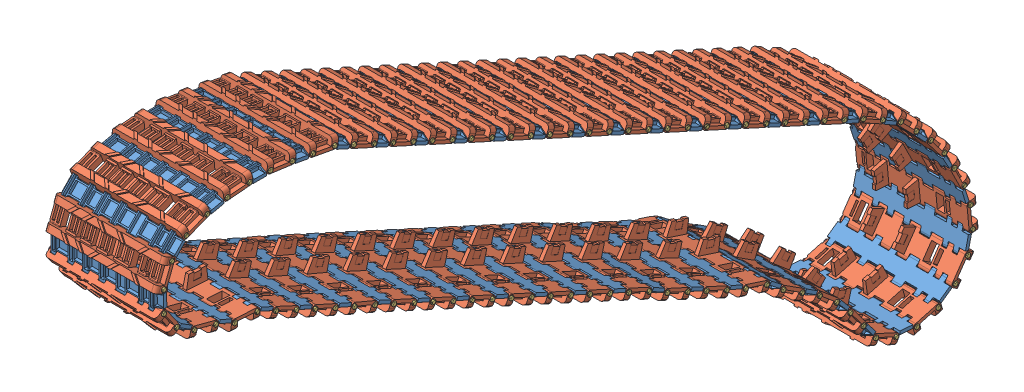
SolidWorks assembly MirrorTREAD (FINAL), configuration Default. Lengths in mm.
Overall size (22.86 95.91 166.24).
270 component instances, 4 part files, 0 mates.
Components (placement in the parent):
- Tread Part 2-1: Tread Part 2 [Default] at (0 0 -26.5717) x (-1 0 0) z (0 0 -1) size (22.53 1.27 5.46)
- Tread Part 1-1: Tread Part 1 [Default] at (20.9139 0.0325 -11.5906) x (-1 0 0) z (0 0.086807 -0.996225) size (22.53 4.95 5.79)
- Linkage Bolt-1: Linkage Bolt [Default] at (25.6791 0.635 -11.1903) x (0 -0.28534 -0.958426) z (1 0 0) size (0.89 0.89 22.86)
- Linkage Nut-1: Linkage Nut [Default] at (3.3271 0.635 -11.1903) x (0 0.279758 0.960071) z (-1 0 0) size (1.17 1.02 0.25)
- Tread Part 1-2: Tread Part 1 [Default] at (20.9139 -16.6165 -59.8831) x (-1 0 0) z (0 -0.414552 -0.910026) size (22.53 4.95 5.79)
- Tread Part 1-3: Tread Part 1 [Default] at (20.9139 -12.9594 5.7016) x (-1 0 0) z (0 0.819649 0.572866) size (22.53 4.95 5.79)
- Tread Part 1-4: Tread Part 1 [Default] at (20.9139 -9.4391 -44.1273) x (-1 0 0) z (0 -0.414552 -0.910026) size (22.53 4.95 5.79)
- Tread Part 1-5: Tread Part 1 [Default] at (20.9139 -1.1036 -3.1964) x (-1 0 0) z (0 0.360184 -0.932881) size (22.53 4.95 5.79)
- Tread Part 1-6: Tread Part 1 [Default] at (20.9139 -13.0278 -52.0052) x (-1 0 0) z (0 -0.414552 -0.910026) size (22.53 4.95 5.79)
- Tread Part 1-7: Tread Part 1 [Default] at (20.9139 -0.6492 -20.0624) x (-1 0 0) z (0 -0.136124 -0.990692) size (22.53 4.95 5.79)
- Tread Part 1-8: Tread Part 1 [Default] at (20.9139 -5.8504 -36.2493) x (-1 0 0) z (0 -0.414552 -0.910026) size (22.53 4.95 5.79)
- Tread Part 1-9: Tread Part 1 [Default] at (20.9139 -5.1562 3.7247) x (-1 0 0) z (0 0.932796 -0.360404) size (22.53 4.95 5.79)
- Tread Part 1-10: Tread Part 1 [Default] at (20.9139 -2.2276 -28.5444) x (-1 0 0) z (0 -0.182095 -0.983281) size (22.53 4.95 5.79)
- Tread Part 2-2: Tread Part 2 [Default] at (0 -15.6718 -57.8094) x (-1 0 0) z (0 -0.414552 -0.910026) size (22.53 1.27 5.46)
- Tread Part 2-3: Tread Part 2 [Default] at (0 1.9852 -17.8142) x (-1 0 0) z (0 0.210774 -0.977535) size (22.53 1.27 5.46)
- Tread Part 2-4: Tread Part 2 [Default] at (0 -3.365 -34.8217) x (-1 0 0) z (0 -0.179921 -0.983681) size (22.53 1.27 5.46)
- Tread Part 2-5: Tread Part 2 [Default] at (0 -19.2605 -65.6873) x (-1 0 0) z (0 -0.414552 -0.910026) size (22.53 1.27 5.46)
- Tread Part 2-6: Tread Part 2 [Default] at (0 1.7781 5.4907) x (-1 0 0) z (0 0.999978 0.006638) size (22.53 1.27 5.46)
- Tread Part 2-7: Tread Part 2 [Default] at (0 5.3393 -6.7315) x (-1 0 0) z (0 0.717252 -0.696814) size (22.53 1.27 5.46)
- Tread Part 2-8: Tread Part 2 [Default] at (0 -8.4944 -42.0535) x (-1 0 0) z (0 -0.414552 -0.910026) size (22.53 1.27 5.46)
- Tread Part 2-9: Tread Part 2 [Default] at (0 -22.8492 -73.5653) x (-1 0 0) z (0 -0.414552 -0.910026) size (22.53 1.27 5.46)
- Tread Part 2-10: Tread Part 2 [Default] at (0 -12.0831 -49.9315) x (-1 0 0) z (0 -0.414552 -0.910026) size (22.53 1.27 5.46)
- Linkage Bolt-2: Linkage Bolt [Default] at (25.6791 -14.0437 -55.7671) x (0 -0.279758 -0.960071) z (1 0 0) size (0.89 0.89 22.86)
- Linkage Bolt-3: Linkage Bolt [Default] at (25.6791 -8.7176 -44.0752) x (0 -0.279758 -0.960071) z (1 0 0) size (0.89 0.89 22.86)
- Linkage Bolt-4: Linkage Bolt [Default] at (25.6791 -5.1289 -36.1973) x (0 -0.279758 -0.960071) z (1 0 0) size (0.89 0.89 22.86)
- Linkage Bolt-5: Linkage Bolt [Default] at (25.6791 -12.3063 -51.9532) x (0 -0.279758 -0.960071) z (1 0 0) size (0.89 0.89 22.86)
- Linkage Bolt-6: Linkage Bolt [Default] at (25.6791 -0.727 -23.9282) x (0 0.859107 0.511795) z (1 0 0) size (0.89 0.89 22.86)
- Linkage Bolt-7: Linkage Bolt [Default] at (25.6791 -6.8663 -40.0112) x (0 -0.279758 -0.960071) z (1 0 0) size (0.89 0.89 22.86)
- Linkage Bolt-8: Linkage Bolt [Default] at (25.6791 -15.895 -59.8311) x (0 -0.279758 -0.960071) z (1 0 0) size (0.89 0.89 22.86)
- Linkage Bolt-9: Linkage Bolt [Default] at (25.6791 -3.2775 -32.1333) x (0 -0.279758 -0.960071) z (1 0 0) size (0.89 0.89 22.86)
- Linkage Bolt-10: Linkage Bolt [Default] at (25.6791 -1.5402 -28.3194) x (0 -0.279758 -0.960071) z (1 0 0) size (0.89 0.89 22.86)
- Linkage Bolt-11: Linkage Bolt [Default] at (25.6791 -10.455 -47.8891) x (0 -0.279758 -0.960071) z (1 0 0) size (0.89 0.89 22.86)
- Linkage Bolt-12: Linkage Bolt [Default] at (25.6791 -17.2675 3.4653) x (0 -0.279758 -0.960071) z (1 0 0) size (0.89 0.89 22.86)
- Linkage Bolt-13: Linkage Bolt [Default] at (25.6791 -13.6071 6.0236) x (0 -0.279758 -0.960071) z (1 0 0) size (0.89 0.89 22.86)
- Linkage Bolt-14: Linkage Bolt [Default] at (25.6791 -5.2505 4.4419) x (0 -0.50378 -0.863832) z (1 0 0) size (0.89 0.89 22.86)
- Linkage Bolt-15: Linkage Bolt [Default] at (25.6791 0.0271 -19.8056) x (0 0.965901 0.258913) z (1 0 0) size (0.89 0.89 22.86)
- Linkage Bolt-16: Linkage Bolt [Default] at (25.6791 0.2473 -6.7414) x (0 -0.279758 -0.960071) z (1 0 0) size (0.89 0.89 22.86)
- Linkage Bolt-17: Linkage Bolt [Default] at (25.6791 -2.2445 1.5215) x (0 -0.279758 -0.960071) z (1 0 0) size (0.89 0.89 22.86)
- Linkage Bolt-18: Linkage Bolt [Default] at (25.6791 -9.4162 6.0514) x (0 -0.820255 0.571998) z (1 0 0) size (0.89 0.89 22.86)
- Linkage Bolt-19: Linkage Bolt [Default] at (25.6791 0.635 -15.3813) x (0 -0.279758 -0.960071) z (1 0 0) size (0.89 0.89 22.86)
- Linkage Bolt-20: Linkage Bolt [Default] at (25.6791 -0.636 -2.6445) x (0 -0.244946 -0.969537) z (1 0 0) size (0.89 0.89 22.86)
- Linkage Nut-2: Linkage Nut [Default] at (3.0731 -0.636 -2.6445) x (0 -0.279758 -0.960071) z (1 0 0) size (1.17 1.02 0.25)
- Linkage Nut-3: Linkage Nut [Default] at (3.0731 -15.895 -59.8311) x (0 -0.279758 -0.960071) z (1 0 0) size (1.17 1.02 0.25)
- Linkage Nut-4: Linkage Nut [Default] at (3.0731 0.635 -15.3813) x (0 -0.279758 -0.960071) z (1 0 0) size (1.17 1.02 0.25)
- Linkage Nut-5: Linkage Nut [Default] at (3.0731 -14.0437 -55.7671) x (0 -0.279758 -0.960071) z (1 0 0) size (1.17 1.02 0.25)
- Linkage Nut-6: Linkage Nut [Default] at (3.0731 -3.2775 -32.1333) x (0 -0.279758 -0.960071) z (1 0 0) size (1.17 1.02 0.25)
- Linkage Nut-7: Linkage Nut [Default] at (3.0731 -5.1289 -36.1973) x (0 -0.279758 -0.960071) z (1 0 0) size (1.17 1.02 0.25)
- Linkage Nut-8: Linkage Nut [Default] at (3.0731 -1.5402 -28.3194) x (0 -0.279758 -0.960071) z (1 0 0) size (1.17 1.02 0.25)
- Linkage Nut-9: Linkage Nut [Default] at (3.0731 -6.8663 -40.0112) x (0 -0.279758 -0.960071) z (1 0 0) size (1.17 1.02 0.25)
- Linkage Nut-10: Linkage Nut [Default] at (3.0731 -0.727 -23.9282) x (0 -0.279758 -0.960071) z (1 0 0) size (1.17 1.02 0.25)
- Linkage Nut-11: Linkage Nut [Default] at (3.0731 -13.6071 6.0236) x (0 -0.279758 -0.960071) z (1 0 0) size (1.17 1.02 0.25)
- Linkage Nut-12: Linkage Nut [Default] at (3.0731 -9.4162 6.0514) x (0 -0.279758 -0.960071) z (1 0 0) size (1.17 1.02 0.25)
- Linkage Nut-13: Linkage Nut [Default] at (3.0731 -8.7176 -44.0752) x (0 -0.279758 -0.960071) z (1 0 0) size (1.17 1.02 0.25)
- Linkage Nut-14: Linkage Nut [Default] at (3.0731 0.0271 -19.8056) x (0 0.537357 -0.843355) z (1 0 0) size (1.17 1.02 0.25)
- Linkage Nut-15: Linkage Nut [Default] at (3.0731 0.2473 -6.7414) x (0 -0.279758 -0.960071) z (1 0 0) size (1.17 1.02 0.25)
- Linkage Nut-16: Linkage Nut [Default] at (3.0731 -17.2675 3.4653) x (0 -0.279758 -0.960071) z (1 0 0) size (1.17 1.02 0.25)
- Linkage Nut-17: Linkage Nut [Default] at (3.0731 -2.2445 1.5215) x (0 -0.279758 -0.960071) z (1 0 0) size (1.17 1.02 0.25)
- Linkage Nut-18: Linkage Nut [Default] at (3.0731 -5.2505 4.4419) x (0 -0.130274 -0.991478) z (1 0 0) size (1.17 1.02 0.25)
- Linkage Nut-19: Linkage Nut [Default] at (3.0731 -12.3063 -51.9532) x (0 -0.279758 -0.960071) z (1 0 0) size (1.17 1.02 0.25)
- Linkage Nut-20: Linkage Nut [Default] at (3.0731 -10.455 -47.8891) x (0 -0.279758 -0.960071) z (1 0 0) size (1.17 1.02 0.25)
- Tread Part 2-11: Tread Part 2 [Default] at (0 -44.4097 -120.8185) x (-1 0 0) z (0 -0.416427 -0.909169) size (22.53 1.27 5.46)
- Tread Part 1-11: Tread Part 1 [Default] at (20.9139 -38.1487 -107.1507) x (-1 0 0) z (0 -0.414552 -0.910026) size (22.53 4.95 5.79)
- Linkage Bolt-21: Linkage Bolt [Default] at (25.6791 -37.4272 -107.0987) x (0 -0.416427 -0.909169) z (1 0 0) size (0.89 0.89 22.86)
- Linkage Nut-21: Linkage Nut [Default] at (3.3271 -37.4272 -107.0987) x (0 0.416427 0.909169) z (-1 0 0) size (1.17 1.02 0.25)
- Tread Part 1-12: Tread Part 1 [Default] at (20.9139 -64.6898 -150.487) x (-1 0 0) z (0 -0.793222 -0.608932) size (22.53 4.95 5.79)
- Tread Part 1-13: Tread Part 1 [Default] at (20.9139 -27.3826 -83.5169) x (-1 0 0) z (0 -0.414552 -0.910026) size (22.53 4.95 5.79)
- Tread Part 1-14: Tread Part 1 [Default] at (20.9139 -52.8597 -138.4334) x (-1 0 0) z (0 -0.48122 -0.8766) size (22.53 4.95 5.79)
- Tread Part 1-15: Tread Part 1 [Default] at (20.9139 -20.2052 -67.7611) x (-1 0 0) z (0 -0.414552 -0.910026) size (22.53 4.95 5.79)
- Tread Part 1-16: Tread Part 1 [Default] at (20.9139 -23.7939 -75.639) x (-1 0 0) z (0 -0.414552 -0.910026) size (22.53 4.95 5.79)
- Tread Part 1-17: Tread Part 1 [Default] at (20.9139 -34.56 -99.2728) x (-1 0 0) z (0 -0.414552 -0.910026) size (22.53 4.95 5.79)
- Tread Part 1-18: Tread Part 1 [Default] at (20.9139 -58.1406 -144.9601) x (-1 0 0) z (0 -0.71534 -0.698777) size (22.53 4.95 5.79)
- Tread Part 1-19: Tread Part 1 [Default] at (20.9139 -41.7537 -115.0197) x (-1 0 0) z (0 -0.416427 -0.909169) size (22.53 4.95 5.79)
- Tread Part 1-20: Tread Part 1 [Default] at (20.9139 -48.9636 -130.7608) x (-1 0 0) z (0 -0.416429 -0.909168) size (22.53 4.95 5.79)
- Tread Part 1-21: Tread Part 1 [Default] at (20.9139 -30.9713 -91.3948) x (-1 0 0) z (0 -0.414552 -0.910026) size (22.53 4.95 5.79)
- Tread Part 1-22: Tread Part 1 [Default] at (20.9139 -45.3587 -122.8902) x (-1 0 0) z (0 -0.416427 -0.909169) size (22.53 4.95 5.79)
- Tread Part 2-12: Tread Part 2 [Default] at (0 -60.4579 -151.3867) x (-1 0 0) z (0 -0.505398 -0.862886) size (22.53 1.27 5.46)
- Tread Part 2-13: Tread Part 2 [Default] at (0 -40.7927 -112.9549) x (-1 0 0) z (0 -0.414552 -0.910026) size (22.53 1.27 5.46)
- Tread Part 2-14: Tread Part 2 [Default] at (0 -48.0147 -128.689) x (-1 0 0) z (0 -0.416427 -0.909169) size (22.53 1.27 5.46)
- Tread Part 2-15: Tread Part 2 [Default] at (0 -69.0325 -155.3119) x (-1 0 0) z (0 -0.724635 -0.689133) size (22.53 1.27 5.46)
- Tread Part 2-16: Tread Part 2 [Default] at (0 -33.6153 -97.199) x (-1 0 0) z (0 -0.414552 -0.910026) size (22.53 1.27 5.46)
- Tread Part 2-17: Tread Part 2 [Default] at (0 -30.0266 -89.3211) x (-1 0 0) z (0 -0.414552 -0.910026) size (22.53 1.27 5.46)
- Tread Part 2-18: Tread Part 2 [Default] at (0 -37.204 -105.077) x (-1 0 0) z (0 -0.414552 -0.910026) size (22.53 1.27 5.46)
- Tread Part 2-19: Tread Part 2 [Default] at (0 -51.6196 -136.5595) x (-1 0 0) z (0 -0.416427 -0.909169) size (22.53 1.27 5.46)
- Tread Part 2-20: Tread Part 2 [Default] at (0 -26.4379 -81.4432) x (-1 0 0) z (0 -0.414552 -0.910026) size (22.53 1.27 5.46)
- Tread Part 2-21: Tread Part 2 [Default] at (0 -77.8314 -157.5963) x (-1 0 0) z (0 -0.877598 -0.479397) size (22.53 1.27 5.46)
- Tread Part 2-22: Tread Part 2 [Default] at (0 -55.2245 -144.43) x (-1 0 0) z (0 -0.416427 -0.909169) size (22.53 1.27 5.46)
- Linkage Bolt-22: Linkage Bolt [Default] at (25.6791 -60.486 -148.0604) x (0 -0.416427 -0.909169) z (1 0 0) size (0.89 0.89 22.86)
- Linkage Bolt-23: Linkage Bolt [Default] at (25.6791 -52.1363 -138.4353) x (0 -0.99376 -0.111543) z (1 0 0) size (0.89 0.89 22.86)
- Linkage Bolt-24: Linkage Bolt [Default] at (25.6791 -48.242 -130.7102) x (0 -0.416427 -0.909169) z (1 0 0) size (0.89 0.89 22.86)
- Linkage Bolt-25: Linkage Bolt [Default] at (25.6791 -57.449 -145.1722) x (0 -0.416427 -0.909169) z (1 0 0) size (0.89 0.89 22.86)
- Linkage Bolt-26: Linkage Bolt [Default] at (25.6791 -42.7774 -118.7795) x (0 -0.416427 -0.909169) z (1 0 0) size (0.89 0.89 22.86)
- Linkage Bolt-27: Linkage Bolt [Default] at (25.6791 -49.9873 -134.5205) x (0 0.416133 -0.909304) z (1 0 0) size (0.89 0.89 22.86)
- Linkage Bolt-28: Linkage Bolt [Default] at (25.6791 -64.0283 -150.7798) x (0 -0.416427 -0.909169) z (1 0 0) size (0.89 0.89 22.86)
- Linkage Bolt-29: Linkage Bolt [Default] at (25.6791 -46.3823 -126.65) x (0 -0.416427 -0.909169) z (1 0 0) size (0.89 0.89 22.86)
- Linkage Bolt-30: Linkage Bolt [Default] at (25.6791 -44.6371 -122.8397) x (0 -0.416427 -0.909169) z (1 0 0) size (0.89 0.89 22.86)
- Linkage Bolt-31: Linkage Bolt [Default] at (25.6791 -54.2544 -142.0516) x (0 0.865619 0.500703) z (1 0 0) size (0.89 0.89 22.86)
- Linkage Bolt-32: Linkage Bolt [Default] at (25.6791 -23.0724 -75.5869) x (0 -0.416427 -0.909169) z (1 0 0) size (0.89 0.89 22.86)
- Linkage Bolt-33: Linkage Bolt [Default] at (25.6791 -24.8098 -79.4009) x (0 -0.416427 -0.909169) z (1 0 0) size (0.89 0.89 22.86)
- Linkage Bolt-34: Linkage Bolt [Default] at (25.6791 -26.6611 -83.4649) x (0 -0.416427 -0.909169) z (1 0 0) size (0.89 0.89 22.86)
- Linkage Bolt-35: Linkage Bolt [Default] at (25.6791 -30.2498 -91.3428) x (0 -0.416494 -0.909139) z (1 0 0) size (0.89 0.89 22.86)
- Linkage Bolt-36: Linkage Bolt [Default] at (25.6791 -41.0321 -114.9692) x (0 -0.416427 -0.909169) z (1 0 0) size (0.89 0.89 22.86)
- Linkage Bolt-37: Linkage Bolt [Default] at (25.6791 -35.5759 -103.0346) x (0 -0.416427 -0.909169) z (1 0 0) size (0.89 0.89 22.86)
- Linkage Bolt-38: Linkage Bolt [Default] at (25.6791 -31.9872 -95.1567) x (0 -0.416427 -0.909169) z (1 0 0) size (0.89 0.89 22.86)
- Linkage Bolt-39: Linkage Bolt [Default] at (25.6791 -28.3985 -87.2788) x (0 -0.416427 -0.909169) z (1 0 0) size (0.89 0.89 22.86)
- Linkage Bolt-40: Linkage Bolt [Default] at (25.6791 -39.1724 -110.909) x (0 0.381485 0.924375) z (1 0 0) size (0.89 0.89 22.86)
- Linkage Bolt-41: Linkage Bolt [Default] at (25.6791 -33.8385 -99.2207) x (0 -0.416427 -0.909169) z (1 0 0) size (0.89 0.89 22.86)
- Linkage Bolt-42: Linkage Bolt [Default] at (25.6791 -17.6324 -63.645) x (0 -0.416427 -0.909169) z (1 0 0) size (0.89 0.89 22.86)
- Linkage Bolt-43: Linkage Bolt [Default] at (25.6791 -19.4837 -67.709) x (0 -0.416427 -0.909169) z (1 0 0) size (0.89 0.89 22.86)
- Linkage Bolt-44: Linkage Bolt [Default] at (25.6791 -21.2211 -71.5229) x (0 -0.325901 -0.945404) z (1 0 0) size (0.89 0.89 22.86)
- Linkage Nut-22: Linkage Nut [Default] at (3.0731 -33.8385 -99.2207) x (0 -0.416427 -0.909169) z (1 0 0) size (1.17 1.02 0.25)
- Linkage Nut-23: Linkage Nut [Default] at (3.0731 -19.4837 -67.709) x (0 -0.416427 -0.909169) z (1 0 0) size (1.17 1.02 0.25)
- Linkage Nut-24: Linkage Nut [Default] at (3.0731 -64.0283 -150.7798) x (0 -0.416427 -0.909169) z (1 0 0) size (1.17 1.02 0.25)
- Linkage Nut-25: Linkage Nut [Default] at (3.0731 -39.1724 -110.909) x (0 -0.416427 -0.909169) z (1 0 0) size (1.17 1.02 0.25)
- Linkage Nut-26: Linkage Nut [Default] at (3.0731 -60.486 -148.0604) x (0 -0.416427 -0.909169) z (1 0 0) size (1.17 1.02 0.25)
- Linkage Nut-27: Linkage Nut [Default] at (3.0731 -46.3823 -126.65) x (0 -0.416427 -0.909169) z (1 0 0) size (1.17 1.02 0.25)
- Linkage Nut-28: Linkage Nut [Default] at (3.0731 -23.0724 -75.5869) x (0 -0.416427 -0.909169) z (1 0 0) size (1.17 1.02 0.25)
- Linkage Nut-29: Linkage Nut [Default] at (3.0731 -48.242 -130.7102) x (0 -0.416427 -0.909169) z (1 0 0) size (1.17 1.02 0.25)
- Linkage Nut-30: Linkage Nut [Default] at (3.0731 -17.6324 -63.645) x (0 -0.416427 -0.909169) z (1 0 0) size (1.17 1.02 0.25)
- Linkage Nut-31: Linkage Nut [Default] at (3.0731 -44.6371 -122.8397) x (0 -0.416427 -0.909169) z (1 0 0) size (1.17 1.02 0.25)
- Linkage Nut-32: Linkage Nut [Default] at (3.0731 -49.9873 -134.5205) x (0 -0.416427 -0.909169) z (1 0 0) size (1.17 1.02 0.25)
- Linkage Nut-33: Linkage Nut [Default] at (3.0731 -42.7774 -118.7795) x (0 -0.416427 -0.909169) z (1 0 0) size (1.17 1.02 0.25)
- Linkage Nut-34: Linkage Nut [Default] at (3.0731 -26.6611 -83.4649) x (0 -0.416427 -0.909169) z (1 0 0) size (1.17 1.02 0.25)
- Linkage Nut-35: Linkage Nut [Default] at (3.0731 -28.3985 -87.2788) x (0 -0.416427 -0.909169) z (1 0 0) size (1.17 1.02 0.25)
- Linkage Nut-36: Linkage Nut [Default] at (3.0731 -52.1363 -138.4353) x (0 -0.416427 -0.909169) z (1 0 0) size (1.17 1.02 0.25)
- Linkage Nut-37: Linkage Nut [Default] at (3.0731 -41.0321 -114.9692) x (0 0.408975 -0.912546) z (1 0 0) size (1.17 1.02 0.25)
- Linkage Nut-38: Linkage Nut [Default] at (3.0731 -21.2211 -71.5229) x (0 -0.416427 -0.909169) z (1 0 0) size (1.17 1.02 0.25)
- Linkage Nut-39: Linkage Nut [Default] at (3.0731 -35.5759 -103.0346) x (0 -0.416427 -0.909169) z (1 0 0) size (1.17 1.02 0.25)
- Linkage Nut-40: Linkage Nut [Default] at (3.0731 -24.8098 -79.4009) x (0 -0.416427 -0.909169) z (1 0 0) size (1.17 1.02 0.25)
- Linkage Nut-41: Linkage Nut [Default] at (3.0731 -31.9872 -95.1567) x (0 -0.416427 -0.909169) z (1 0 0) size (1.17 1.02 0.25)
- Linkage Nut-42: Linkage Nut [Default] at (3.0731 -30.2498 -91.3428) x (0 -0.273101 -0.961985) z (1 0 0) size (1.17 1.02 0.25)
- Linkage Nut-43: Linkage Nut [Default] at (3.0731 -57.449 -145.1722) x (0 -0.416427 -0.909169) z (1 0 0) size (1.17 1.02 0.25)
- Linkage Nut-44: Linkage Nut [Default] at (3.0731 -54.2544 -142.0516) x (0 -0.416427 -0.909169) z (1 0 0) size (1.17 1.02 0.25)
- Tread Part 2-23: Tread Part 2 [Default] at (0 -70.3173 -122.3278) x (-1 0 0) z (0 0.758496 0.651678) size (22.53 1.27 5.46)
- Tread Part 1-23: Tread Part 1 [Default] at (20.9139 -81.741 -132.1728) x (-1 0 0) z (0 0.802593 0.596528) size (22.53 4.95 5.79)
- Linkage Bolt-45: Linkage Bolt [Default] at (25.6791 -82.3978 -131.8698) x (0 0.416427 0.909169) z (1 0 0) size (0.89 0.89 22.86)
- Linkage Nut-45: Linkage Nut [Default] at (3.3271 -82.3978 -131.8698) x (0 -0.416427 -0.909169) z (-1 0 0) size (1.17 1.02 0.25)
- Tread Part 1-24: Tread Part 1 [Default] at (20.9139 -55.9034 -87.3592) x (-1 0 0) z (0 0.416427 0.909169) size (22.53 4.95 5.79)
- Tread Part 1-25: Tread Part 1 [Default] at (20.9139 -87.8307 -152.2683) x (-1 0 0) z (0 -0.823045 0.567976) size (22.53 4.95 5.79)
- Tread Part 1-26: Tread Part 1 [Default] at (20.9139 -63.4172 -102.9547) x (-1 0 0) z (0 0.42726 0.904129) size (22.53 4.95 5.79)
- Tread Part 1-27: Tread Part 1 [Default] at (20.9139 -72.2987 -154.3611) x (-1 0 0) z (0 -0.895595 -0.444871) size (22.53 4.95 5.79)
- Tread Part 1-28: Tread Part 1 [Default] at (20.9139 -80.551 -155.8642) x (-1 0 0) z (0 -0.995577 -0.093948) size (22.53 4.95 5.79)
- Tread Part 1-29: Tread Part 1 [Default] at (20.9139 -88.6241 -136.9833) x (-1 0 0) z (0 0.416427 0.909169) size (22.53 4.95 5.79)
- Tread Part 1-30: Tread Part 1 [Default] at (20.9139 -59.8064 -95.0787) x (-1 0 0) z (0 0.416629 0.909076) size (22.53 4.95 5.79)
- Tread Part 1-31: Tread Part 1 [Default] at (20.9139 -75.6254 -125.8755) x (-1 0 0) z (0 0.646019 0.763322) size (22.53 4.95 5.79)
- Tread Part 1-32: Tread Part 1 [Default] at (20.9139 -67.0043 -110.7466) x (-1 0 0) z (0 0.310064 0.950716) size (22.53 4.95 5.79)
- Tread Part 1-33: Tread Part 1 [Default] at (20.9139 -91.0084 -144.77) x (-1 0 0) z (0 -0.265401 0.964138) size (22.53 4.95 5.79)
- Tread Part 1-34: Tread Part 1 [Default] at (20.9139 -70.9384 -118.4945) x (-1 0 0) z (0 0.540052 0.841631) size (22.53 4.95 5.79)
- Tread Part 2-24: Tread Part 2 [Default] at (0 -57.1368 -89.287) x (-1 0 0) z (0 0.417754 0.90856) size (22.53 1.27 5.46)
- Tread Part 2-25: Tread Part 2 [Default] at (0 -76.622 -128.3681) x (-1 0 0) z (0 0.802593 0.596528) size (22.53 1.27 5.46)
- Tread Part 2-26: Tread Part 2 [Default] at (0 -67.4969 -113.1243) x (-1 0 0) z (0 0.539775 0.841809) size (22.53 1.27 5.46)
- Tread Part 2-27: Tread Part 2 [Default] at (0 -96.3343 -140.1053) x (-1 0 0) z (0 -0.581528 0.813527) size (22.53 1.27 5.46)
- Tread Part 2-28: Tread Part 2 [Default] at (0 -94.9938 -152.3964) x (-1 0 0) z (0 -0.974542 0.224206) size (22.53 1.27 5.46)
- Tread Part 2-29: Tread Part 2 [Default] at (0 -89.7091 -129.986) x (-1 0 0) z (0 0.077134 0.997021) size (22.53 1.27 5.46)
- Tread Part 2-30: Tread Part 2 [Default] at (0 -86.5579 -158.8264) x (-1 0 0) z (0 -0.953086 -0.3027) size (22.53 1.27 5.46)
- Tread Part 2-31: Tread Part 2 [Default] at (0 -49.6425 -73.6899) x (-1 0 0) z (0 0.416427 0.909169) size (22.53 1.27 5.46)
- Tread Part 2-32: Tread Part 2 [Default] at (0 -61.0114 -97.021) x (-1 0 0) z (0 0.397978 0.917395) size (22.53 1.27 5.46)
- Linkage Bolt-46: Linkage Bolt [Default] at (25.6791 -58.4847 -91.4699) x (0 0.416427 0.909169) z (1 0 0) size (0.89 0.89 22.86)
- Linkage Bolt-47: Linkage Bolt [Default] at (25.6791 -64.1394 -102.9966) x (0 0.416427 0.909169) z (1 0 0) size (0.89 0.89 22.86)
- Linkage Bolt-48: Linkage Bolt [Default] at (25.6791 -67.7154 -110.8791) x (0 0.416427 0.909169) z (1 0 0) size (0.89 0.89 22.86)
- Linkage Bolt-49: Linkage Bolt [Default] at (25.6791 -60.528 -95.1291) x (0 0.416427 0.909169) z (1 0 0) size (0.89 0.89 22.86)
- Linkage Bolt-50: Linkage Bolt [Default] at (25.6791 -74.0718 -122.2017) x (0 0.416427 0.909169) z (1 0 0) size (0.89 0.89 22.86)
- Linkage Bolt-51: Linkage Bolt [Default] at (25.6791 -66.0475 -107.0343) x (0 0.416427 0.909169) z (1 0 0) size (0.89 0.89 22.86)
- Linkage Bolt-52: Linkage Bolt [Default] at (25.6791 -56.625 -87.4097) x (0 0.416427 0.909169) z (1 0 0) size (0.89 0.89 22.86)
- Linkage Bolt-53: Linkage Bolt [Default] at (25.6791 -69.1001 -115.1248) x (0 0.416427 0.909169) z (1 0 0) size (0.89 0.89 22.86)
- Linkage Bolt-54: Linkage Bolt [Default] at (25.6791 -71.66 -118.4432) x (0 0.416427 0.909169) z (1 0 0) size (0.89 0.89 22.86)
- Linkage Bolt-55: Linkage Bolt [Default] at (25.6791 -62.3886 -99.1888) x (0 0.416427 0.909169) z (1 0 0) size (0.89 0.89 22.86)
- Linkage Bolt-56: Linkage Bolt [Default] at (25.6791 -80.1464 -156.4638) x (0 0.416427 0.909169) z (1 0 0) size (0.89 0.89 22.86)
- Linkage Bolt-57: Linkage Bolt [Default] at (25.6791 -84.2307 -155.5242) x (0 0.416427 0.909169) z (1 0 0) size (0.89 0.89 22.86)
- Linkage Bolt-58: Linkage Bolt [Default] at (25.6791 -87.9063 -152.9877) x (0 0.555724 -0.831367) z (1 0 0) size (0.89 0.89 22.86)
- Linkage Bolt-59: Linkage Bolt [Default] at (25.6791 -91.5287 -145.2725) x (0 0.416494 0.909139) z (1 0 0) size (0.89 0.89 22.86)
- Linkage Bolt-60: Linkage Bolt [Default] at (25.6791 -76.334 -125.7298) x (0 0.416427 0.909169) z (1 0 0) size (0.89 0.89 22.86)
- Linkage Bolt-61: Linkage Bolt [Default] at (25.6791 -85.9821 -134.5338) x (0 -0.255775 0.966736) z (1 0 0) size (0.89 0.89 22.86)
- Linkage Bolt-62: Linkage Bolt [Default] at (25.6791 -91.2054 -141.094) x (0 0.416427 0.909169) z (1 0 0) size (0.89 0.89 22.86)
- Linkage Bolt-63: Linkage Bolt [Default] at (25.6791 -90.3434 -149.5782) x (0 0.416427 0.909169) z (1 0 0) size (0.89 0.89 22.86)
- Linkage Bolt-64: Linkage Bolt [Default] at (25.6791 -79.219 -129.1386) x (0 0.416427 0.909169) z (1 0 0) size (0.89 0.89 22.86)
- Linkage Bolt-65: Linkage Bolt [Default] at (25.6791 -89.3457 -137.0338) x (0 0.416427 0.909169) z (1 0 0) size (0.89 0.89 22.86)
- Linkage Bolt-66: Linkage Bolt [Default] at (25.6791 -67.7064 -152.7889) x (0 0.416427 0.909169) z (1 0 0) size (0.89 0.89 22.86)
- Linkage Bolt-67: Linkage Bolt [Default] at (25.6791 -71.7059 -154.7756) x (0 -0.959191 0.282758) z (1 0 0) size (0.89 0.89 22.86)
- Linkage Bolt-68: Linkage Bolt [Default] at (25.6791 -75.7003 -156.0443) x (0 0.325901 0.945404) z (1 0 0) size (0.89 0.89 22.86)
- Linkage Nut-46: Linkage Nut [Default] at (3.0731 -89.3457 -137.0338) x (0 0.416427 0.909169) z (1 0 0) size (1.17 1.02 0.25)
- Linkage Nut-47: Linkage Nut [Default] at (3.0731 -71.7059 -154.7756) x (0 0.416427 0.909169) z (1 0 0) size (1.17 1.02 0.25)
- Linkage Nut-48: Linkage Nut [Default] at (3.0731 -56.625 -87.4097) x (0 0.416427 0.909169) z (1 0 0) size (1.17 1.02 0.25)
- Linkage Nut-49: Linkage Nut [Default] at (3.0731 -79.219 -129.1386) x (0 0.416427 0.909169) z (1 0 0) size (1.17 1.02 0.25)
- Linkage Nut-50: Linkage Nut [Default] at (3.0731 -58.4847 -91.4699) x (0 0.416427 0.909169) z (1 0 0) size (1.17 1.02 0.25)
- Linkage Nut-51: Linkage Nut [Default] at (3.0731 -69.1001 -115.1248) x (0 0.416427 0.909169) z (1 0 0) size (1.17 1.02 0.25)
- Linkage Nut-52: Linkage Nut [Default] at (3.0731 -80.1464 -156.4638) x (0 0.416427 0.909169) z (1 0 0) size (1.17 1.02 0.25)
- Linkage Nut-53: Linkage Nut [Default] at (3.0731 -67.7154 -110.8791) x (0 0.416427 0.909169) z (1 0 0) size (1.17 1.02 0.25)
- Linkage Nut-54: Linkage Nut [Default] at (3.0731 -67.7064 -152.7889) x (0 0.416427 0.909169) z (1 0 0) size (1.17 1.02 0.25)
- Linkage Nut-55: Linkage Nut [Default] at (3.0731 -71.66 -118.4432) x (0 0.416427 0.909169) z (1 0 0) size (1.17 1.02 0.25)
- Linkage Nut-56: Linkage Nut [Default] at (3.0731 -66.0475 -107.0343) x (0 0.416427 0.909169) z (1 0 0) size (1.17 1.02 0.25)
- Linkage Nut-57: Linkage Nut [Default] at (3.0731 -74.0718 -122.2017) x (0 0.416427 0.909169) z (1 0 0) size (1.17 1.02 0.25)
- Linkage Nut-58: Linkage Nut [Default] at (3.0731 -87.9063 -152.9877) x (0 0.416427 0.909169) z (1 0 0) size (1.17 1.02 0.25)
- Linkage Nut-59: Linkage Nut [Default] at (3.0731 -90.3434 -149.5782) x (0 0.416427 0.909169) z (1 0 0) size (1.17 1.02 0.25)
- Linkage Nut-60: Linkage Nut [Default] at (3.0731 -64.1394 -102.9966) x (0 0.416427 0.909169) z (1 0 0) size (1.17 1.02 0.25)
- Linkage Nut-61: Linkage Nut [Default] at (3.0731 -76.334 -125.7298) x (0 -0.408975 0.912546) z (1 0 0) size (1.17 1.02 0.25)
- Linkage Nut-62: Linkage Nut [Default] at (3.0731 -75.7003 -156.0443) x (0 0.416427 0.909169) z (1 0 0) size (1.17 1.02 0.25)
- Linkage Nut-63: Linkage Nut [Default] at (3.0731 -85.9821 -134.5338) x (0 0.416427 0.909169) z (1 0 0) size (1.17 1.02 0.25)
- Linkage Nut-64: Linkage Nut [Default] at (3.0731 -84.2307 -155.5242) x (0 0.416427 0.909169) z (1 0 0) size (1.17 1.02 0.25)
- Linkage Nut-65: Linkage Nut [Default] at (3.0731 -91.2054 -141.094) x (0 0.416427 0.909169) z (1 0 0) size (1.17 1.02 0.25)
- Linkage Nut-66: Linkage Nut [Default] at (3.0731 -91.5287 -145.2725) x (0 0.273101 0.961985) z (1 0 0) size (1.17 1.02 0.25)
- Linkage Nut-67: Linkage Nut [Default] at (3.0731 -60.528 -95.1291) x (0 0.416427 0.909169) z (1 0 0) size (1.17 1.02 0.25)
- Linkage Nut-68: Linkage Nut [Default] at (3.0731 -62.3886 -99.1888) x (0 0.416427 0.909169) z (1 0 0) size (1.17 1.02 0.25)
- Tread Part 2-33: Tread Part 2 [Default] at (0 -38.8276 -50.0784) x (-1 0 0) z (0 0.416427 0.909169) size (22.53 1.27 5.46)
- Tread Part 1-35: Tread Part 1 [Default] at (20.9139 -45.0886 -63.7476) x (-1 0 0) z (0 0.416427 0.909169) size (22.53 4.95 5.79)
- Linkage Bolt-69: Linkage Bolt [Default] at (25.6791 -45.8102 -63.7982) x (0 0.416427 0.909169) z (1 0 0) size (0.89 0.89 22.86)
- Linkage Nut-69: Linkage Nut [Default] at (3.3271 -45.8102 -63.7982) x (0 -0.416427 -0.909169) z (-1 0 0) size (1.17 1.02 0.25)
- Tread Part 1-36: Tread Part 1 [Default] at (20.9139 -23.6233 -16.4556) x (-1 0 0) z (0 0.421185 0.906975) size (22.53 4.95 5.79)
- Tread Part 1-37: Tread Part 1 [Default] at (20.9139 -30.7911 -32.1913) x (-1 0 0) z (0 0.389464 0.921042) size (22.53 4.95 5.79)
- Tread Part 1-38: Tread Part 1 [Default] at (20.9139 -48.6935 -71.6181) x (-1 0 0) z (0 0.416427 0.909169) size (22.53 4.95 5.79)
- Tread Part 1-39: Tread Part 1 [Default] at (20.9139 -27.2511 -24.3092) x (-1 0 0) z (0 0.412867 0.910791) size (22.53 4.95 5.79)
- Tread Part 1-40: Tread Part 1 [Default] at (20.9139 -41.4836 -55.8771) x (-1 0 0) z (0 0.416427 0.909169) size (22.53 4.95 5.79)
- Tread Part 1-41: Tread Part 1 [Default] at (20.9139 -34.2738 -40.1361) x (-1 0 0) z (0 0.416427 0.909169) size (22.53 4.95 5.79)
- Tread Part 1-42: Tread Part 1 [Default] at (20.9139 -52.2985 -79.4887) x (-1 0 0) z (0 0.416427 0.909169) size (22.53 4.95 5.79)
- Tread Part 1-43: Tread Part 1 [Default] at (20.9139 -37.8787 -48.0066) x (-1 0 0) z (0 0.416427 0.909169) size (22.53 4.95 5.79)
- Tread Part 2-34: Tread Part 2 [Default] at (0 -24.7109 -18.4519) x (-1 0 0) z (0 0.404335 0.914611) size (22.53 1.27 5.46)
- Tread Part 2-35: Tread Part 2 [Default] at (0 -42.4326 -57.9489) x (-1 0 0) z (0 0.416427 0.909169) size (22.53 1.27 5.46)
- Tread Part 2-36: Tread Part 2 [Default] at (0 -20.9857 -10.6449) x (-1 0 0) z (0 0.416712 0.909039) size (22.53 1.27 5.46)
- Tread Part 2-37: Tread Part 2 [Default] at (0 -46.0375 -65.8194) x (-1 0 0) z (0 0.416427 0.909169) size (22.53 1.27 5.46)
- Tread Part 2-38: Tread Part 2 [Default] at (0 -31.6178 -34.3373) x (-1 0 0) z (0 0.416427 0.909169) size (22.53 1.27 5.46)
- Tread Part 2-39: Tread Part 2 [Default] at (0 -28.0128 -26.4668) x (-1 0 0) z (0 0.416427 0.909169) size (22.53 1.27 5.46)
- Linkage Bolt-70: Linkage Bolt [Default] at (25.6791 -26.2261 -20.5527) x (0 0.416427 0.909169) z (1 0 0) size (0.89 0.89 22.86)
- Linkage Bolt-71: Linkage Bolt [Default] at (25.6791 -31.5108 -32.2631) x (0 0.416427 0.909169) z (1 0 0) size (0.89 0.89 22.86)
- Linkage Bolt-72: Linkage Bolt [Default] at (25.6791 -34.9954 -40.1866) x (0 0.416427 0.909169) z (1 0 0) size (0.89 0.89 22.86)
- Linkage Bolt-73: Linkage Bolt [Default] at (25.6791 -27.9725 -24.3625) x (0 0.416427 0.909169) z (1 0 0) size (0.89 0.89 22.86)
- Linkage Bolt-74: Linkage Bolt [Default] at (25.6791 -40.46 -52.1173) x (0 0.416427 0.909169) z (1 0 0) size (0.89 0.89 22.86)
- Linkage Bolt-75: Linkage Bolt [Default] at (25.6791 -33.2501 -36.3763) x (0 0.416427 0.909169) z (1 0 0) size (0.89 0.89 22.86)
- Linkage Bolt-76: Linkage Bolt [Default] at (25.6791 -24.3451 -16.5024) x (0 0.416427 0.909169) z (1 0 0) size (0.89 0.89 22.86)
- Linkage Bolt-77: Linkage Bolt [Default] at (25.6791 -36.8551 -44.2468) x (0 0.416427 0.909169) z (1 0 0) size (0.89 0.89 22.86)
- Linkage Bolt-78: Linkage Bolt [Default] at (25.6791 -38.6003 -48.0571) x (0 0.416427 0.909169) z (1 0 0) size (0.89 0.89 22.86)
- Linkage Bolt-79: Linkage Bolt [Default] at (25.6791 -29.8163 -28.43) x (0 0.416427 0.909169) z (1 0 0) size (0.89 0.89 22.86)
- Linkage Bolt-80: Linkage Bolt [Default] at (25.6791 -53.0201 -79.5392) x (0 0.416494 0.909139) z (1 0 0) size (0.89 0.89 22.86)
- Linkage Bolt-81: Linkage Bolt [Default] at (25.6791 -42.2052 -55.9277) x (0 0.416427 0.909169) z (1 0 0) size (0.89 0.89 22.86)
- Linkage Bolt-82: Linkage Bolt [Default] at (25.6791 -47.6699 -67.8584) x (0 0.416427 0.909169) z (1 0 0) size (0.89 0.89 22.86)
- Linkage Bolt-83: Linkage Bolt [Default] at (25.6791 -51.2748 -75.7289) x (0 0.416427 0.909169) z (1 0 0) size (0.89 0.89 22.86)
- Linkage Bolt-84: Linkage Bolt [Default] at (25.6791 -54.8797 -83.5994) x (0 -0.2284 0.973567) z (1 0 0) size (0.89 0.89 22.86)
- Linkage Bolt-85: Linkage Bolt [Default] at (25.6791 -44.0649 -59.9878) x (0 0.416427 0.909169) z (1 0 0) size (0.89 0.89 22.86)
- Linkage Bolt-86: Linkage Bolt [Default] at (25.6791 -49.4151 -71.6687) x (0 0.416427 0.909169) z (1 0 0) size (0.89 0.89 22.86)
- Linkage Nut-70: Linkage Nut [Default] at (3.0731 -49.4151 -71.6687) x (0 0.416427 0.909169) z (1 0 0) size (1.17 1.02 0.25)
- Linkage Nut-71: Linkage Nut [Default] at (3.0731 -24.3451 -16.5024) x (0 0.416427 0.909169) z (1 0 0) size (1.17 1.02 0.25)
- Linkage Nut-72: Linkage Nut [Default] at (3.0731 -44.0649 -59.9878) x (0 0.416427 0.909169) z (1 0 0) size (1.17 1.02 0.25)
- Linkage Nut-73: Linkage Nut [Default] at (3.0731 -26.2261 -20.5527) x (0 0.416427 0.909169) z (1 0 0) size (1.17 1.02 0.25)
- Linkage Nut-74: Linkage Nut [Default] at (3.0731 -36.8551 -44.2468) x (0 0.416427 0.909169) z (1 0 0) size (1.17 1.02 0.25)
- Linkage Nut-75: Linkage Nut [Default] at (3.0731 -34.9954 -40.1866) x (0 0.416427 0.909169) z (1 0 0) size (1.17 1.02 0.25)
- Linkage Nut-76: Linkage Nut [Default] at (3.0731 -38.6003 -48.0571) x (0 0.416427 0.909169) z (1 0 0) size (1.17 1.02 0.25)
- Linkage Nut-77: Linkage Nut [Default] at (3.0731 -33.2501 -36.3763) x (0 0.416427 0.909169) z (1 0 0) size (1.17 1.02 0.25)
- Linkage Nut-78: Linkage Nut [Default] at (3.0731 -40.46 -52.1173) x (0 0.416427 0.909169) z (1 0 0) size (1.17 1.02 0.25)
- Linkage Nut-79: Linkage Nut [Default] at (3.0731 -54.8797 -83.5994) x (0 0.416427 0.909169) z (1 0 0) size (1.17 1.02 0.25)
- Linkage Nut-80: Linkage Nut [Default] at (3.0731 -31.5108 -32.2631) x (0 0.416427 0.909169) z (1 0 0) size (1.17 1.02 0.25)
- Linkage Nut-81: Linkage Nut [Default] at (3.0731 -42.2052 -55.9277) x (0 -0.408975 0.912546) z (1 0 0) size (1.17 1.02 0.25)
- Linkage Nut-82: Linkage Nut [Default] at (3.0731 -47.6699 -67.8584) x (0 0.416427 0.909169) z (1 0 0) size (1.17 1.02 0.25)
- Linkage Nut-83: Linkage Nut [Default] at (3.0731 -51.2748 -75.7289) x (0 0.416427 0.909169) z (1 0 0) size (1.17 1.02 0.25)
- Linkage Nut-84: Linkage Nut [Default] at (3.0731 -53.0201 -79.5392) x (0 0.273101 0.961985) z (1 0 0) size (1.17 1.02 0.25)
- Linkage Nut-85: Linkage Nut [Default] at (3.0731 -27.9725 -24.3625) x (0 0.416427 0.909169) z (1 0 0) size (1.17 1.02 0.25)
- Linkage Nut-86: Linkage Nut [Default] at (3.0731 -29.8163 -28.43) x (0 0.416427 0.909169) z (1 0 0) size (1.17 1.02 0.25)
- Tread Part 2-40: Tread Part 2 [Default] at (0 -52.4744 -82.0092) x (-1 0 0) z (0 0.487547 0.873097) size (22.53 1.27 5.46)
- Tread Part 2-41: Tread Part 2 [Default] at (0 -35.2227 -42.2078) x (-1 0 0) z (0 0.416427 0.909169) size (22.53 1.27 5.46)
- Tread Part 1-44: Tread Part 1 [Default] at (20.9139 -18.8066 0.0965) x (-1 0 0) z (0 0.255963 0.966687) size (22.53 4.95 5.79)
- Tread Part 2-42: Tread Part 2 [Default] at (0 -10.7458 12.5808) x (-1 0 0) z (0 0.534859 0.844941) size (22.53 1.27 5.46)
- Linkage Bolt-87: Linkage Bolt [Default] at (25.6791 -20.6522 -4.3929) x (0 -0.542931 -0.839777) z (1 0 0) size (0.89 0.89 22.86)
- Linkage Bolt-88: Linkage Bolt [Default] at (25.6791 -19.5091 -0.0759) x (0 0.132174 0.991227) z (1 0 0) size (0.89 0.89 22.86)
- Linkage Nut-87: Linkage Nut [Default] at (3.0731 -19.5091 -0.0759) x (0 -0.279758 -0.960071) z (1 0 0) size (1.17 1.02 0.25)
- Linkage Nut-88: Linkage Nut [Default] at (3.0731 -20.6522 -4.3929) x (0 -0.279758 -0.960071) z (1 0 0) size (1.17 1.02 0.25)
- Tread Part 1-45: Tread Part 1 [Default] at (20.9139 -21.663 -7.9317) x (-1 0 0) z (0 0.06111 0.998131) size (22.53 4.95 5.79)
- Tread Part 2-43: Tread Part 2 [Default] at (0 -61.7621 -106.6524) x (-1 0 0) z (0 0.610811 0.791776) size (22.53 1.27 5.46)
- Tread Part 2-44: Tread Part 2 [Default] at (0 -17.3302 -2.7991) x (-1 0 0) z (0 0.418576 0.908182) size (22.53 1.27 5.46)
- Tread Part 2-45: Tread Part 2 [Default] at (0 -15.6219 5.6232) x (-1 0 0) z (0 0.397454 0.917622) size (22.53 1.27 5.46)
- Linkage Bolt-89: Linkage Bolt [Default] at (25.6791 -22.5909 -12.6962) x (0 0.416427 0.909169) z (1 0 0) size (0.89 0.89 22.86)
- Linkage Bolt-90: Linkage Bolt [Default] at (25.6791 -22.318 -8.2387) x (0 -0.14408 -0.989566) z (1 0 0) size (0.89 0.89 22.86)
- Linkage Nut-89: Linkage Nut [Default] at (3.0731 -22.318 -8.2387) x (0 0.416427 0.909169) z (1 0 0) size (1.17 1.02 0.25)
- Linkage Nut-90: Linkage Nut [Default] at (3.0731 -22.5909 -12.6962) x (0 0.416427 0.909169) z (1 0 0) size (1.17 1.02 0.25)
